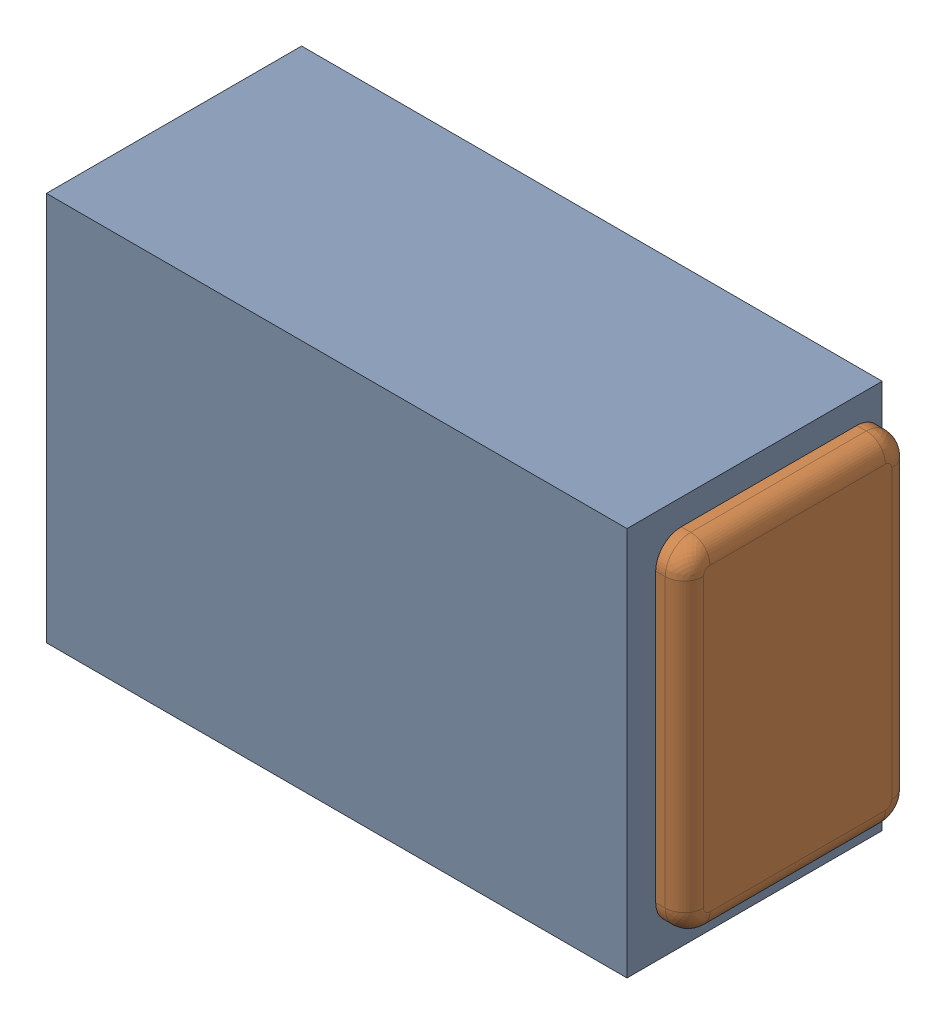
SolidWorks assembly C17, configuration Default. Lengths in mm.
Overall size (1 0.61 0.4).
3 component instances, 2 part files, 0 mates.
Components (placement in the parent):
- 1088880352-1: 1088880352 [Default] at (15.175 19.6 0) size (0.91 0.61 0.4)
  - Extruded-28-1: Extruded-28 [Default] at origin size (0.91 0.61 0.4)
- C0402-1: C0402 [Default] at (15.1749 19.5999 0) x (-1 0 0) z (0 1 0) size (1 0.36 0.54)
